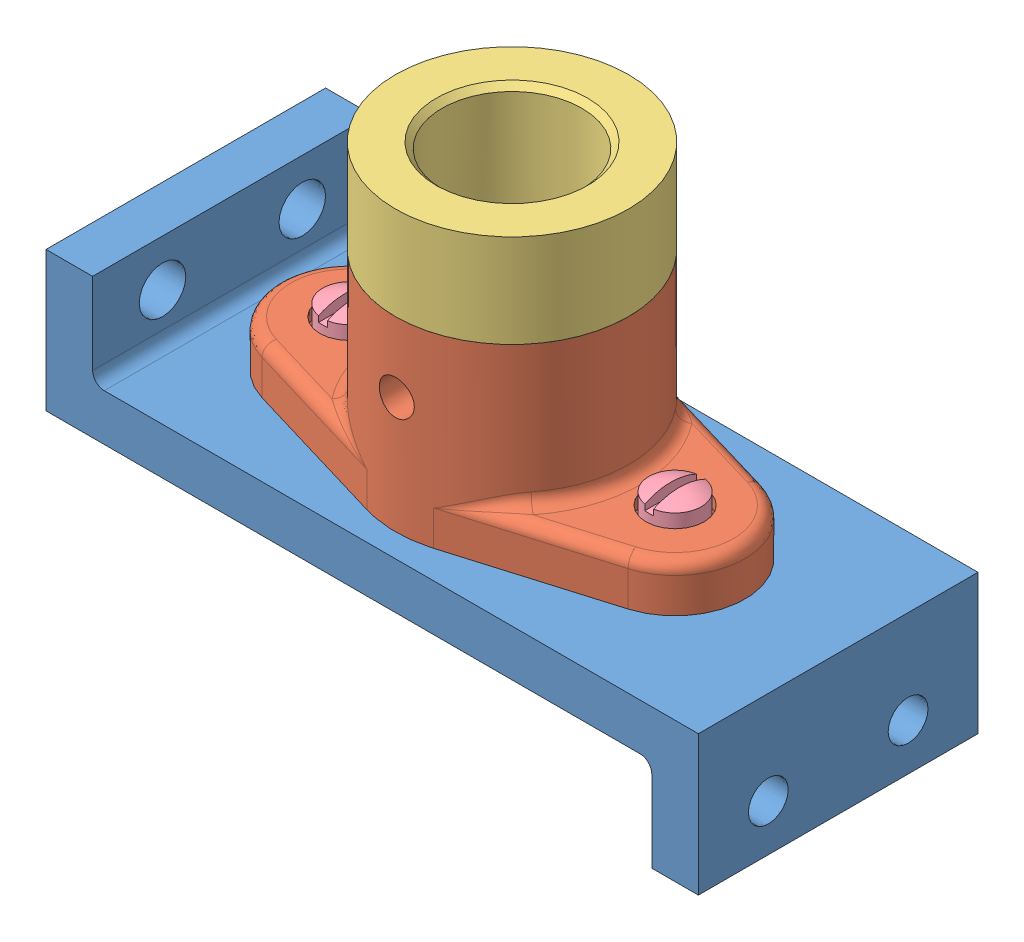
SolidWorks assembly cayoK_Su2022_Module5_Assembly, configuration Default. Lengths in mm.
Overall size (177.8 114.3 76.2).
5 component instances, 4 part files, 13 mates.
Components (placement in the parent):
- M5-BasePlate-to-download-1: M5-BasePlate-to-download [Default] at origin size (177.8 63.5 76.2)
- M5-Bearing-to-download-2: M5-Bearing-to-download [Default] at (0 7.8073 38.1) x (0 0 -1) z (1 0 0) size (63.5 50.8 127)
- M5-Collar-to-download-1: M5-Collar-to-download [Default] at (0 72.6061 38.1) x (0 -1 0) z (0 0 1) size (31.75 63.5 63.5)
- M5-CapScrew-to-download-1: M5-CapScrew-to-download [Default] at (44.45 -1.7177 38.1) x (0 -1 0) z (0 0 1) size (27.79 14.3 14.3)
- M5-CapScrew-to-download-2: M5-CapScrew-to-download [Default] at (-44.45 -1.7177 38.1) x (0 -1 0) z (0 0 1) size (27.79 14.3 14.3)
Mates (geometry in assembly coordinates):
- Coincident3: coincident anti-aligned: plane of M5-BasePlate-to-download-1 through (-73.025 7.8073 76.2) normal (0 1 0); plane of M5-Bearing-to-download-2 through (-44.45 7.8073 38.1) normal (0 -1 0)
- Concentric2: concentric aligned: cylinder of M5-BasePlate-to-download-1 through (44.45 -30.2927 38.1) axis (0 1 0) radius 4.7625; cylinder of M5-Bearing-to-download-2 through (44.45 7.8073 38.1) axis (0 1 0) radius 4.7625
- Concentric4: concentric aligned: cylinder of M5-BasePlate-to-download-1 through (-44.45 -30.2927 38.1) axis (0 1 0) radius 4.7625; cylinder of M5-Bearing-to-download-2 through (-44.45 7.8073 38.1) axis (0 1 0) radius 4.7625
- Concentric5: concentric aligned: cylinder of M5-BasePlate-to-download-1 through (0 -30.2927 38.1) axis (0 1 0) radius 22.225; cylinder of M5-Bearing-to-download-2 through (0 7.8073 38.1) axis (0 1 0) radius 19.05
- Coincident6: coincident anti-aligned: plane of M5-Bearing-to-download-2 through (0 58.6073 38.1) normal (0 1 0); plane of M5-Collar-to-download-1 through (25.4 58.6073 38.1) normal (0 -1 0)
- Concentric8: concentric aligned: cylinder of M5-Bearing-to-download-2 through (0 7.8073 38.1) axis (0 1 0) radius 19.05; cylinder of M5-Collar-to-download-1 through (0 93.2436 38.1) axis (0 1 0) radius 19.05
- Parallel7: parallel aligned: plane of M5-BasePlate-to-download-1 through (-73.025 10.9823 76.2) normal (0 0 1); plane of M5-Collar-to-download-1 through (0 72.6061 38.1) normal (0 0 1)
- Coincident8: coincident anti-aligned: plane of M5-Bearing-to-download-2 through (44.45 17.3323 38.1) normal (0 1 0); plane of M5-CapScrew-to-download-1 through (49.2125 17.3323 38.1) normal (0 -1 0)
- Coincident9: coincident aligned: line of M5-Bearing-to-download-2 through (44.45 17.3323 38.1) axis (0 -1 0); line of M5-CapScrew-to-download-1 through (44.45 17.3323 38.1) axis (0 -1 0)
- Coincident10: coincident anti-aligned: plane of M5-Bearing-to-download-2 through (-44.45 17.3323 38.1) normal (0 1 0); plane of M5-CapScrew-to-download-2 through (-39.6875 17.3323 38.1) normal (0 -1 0)
- Coincident11: coincident anti-aligned: line of M5-BasePlate-to-download-1 through (-44.45 -4.8927 38.1) axis (0 1 0); line of M5-CapScrew-to-download-2 through (-44.45 17.3323 38.1) axis (0 -1 0)
- Parallel8: parallel aligned: plane of M5-BasePlate-to-download-1 through (-73.025 10.9823 76.2) normal (0 0 1); plane of M5-CapScrew-to-download-1 through (44.45 -1.7177 38.1) normal (0 0 1)
- Parallel9: parallel aligned: plane of M5-BasePlate-to-download-1 through (-73.025 10.9823 76.2) normal (0 0 1); plane of M5-CapScrew-to-download-2 through (-44.45 -1.7177 38.1) normal (0 0 1)
